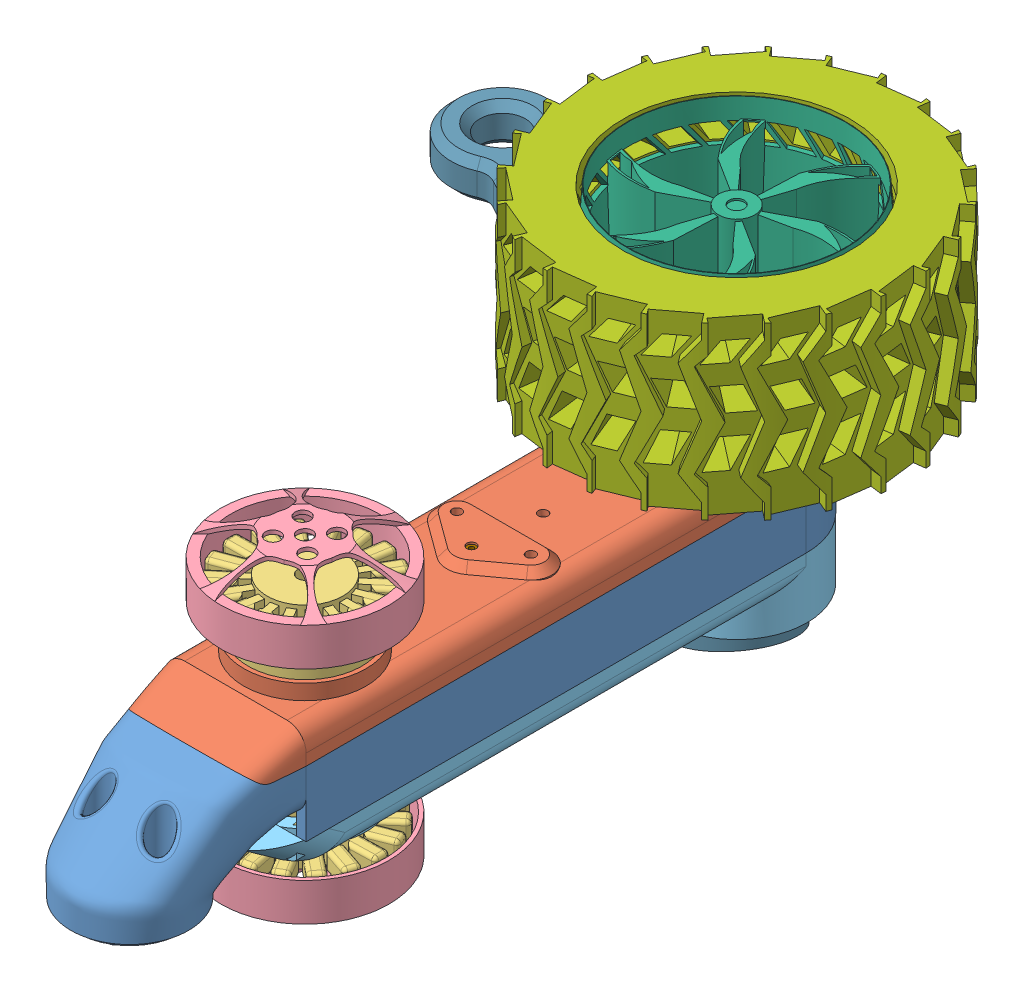
SolidWorks assembly actuator core v2, configuration Default. Lengths in mm.
Overall size (225.57 108.76 271.87).
33 component instances, 15 part files, 37 mates.
Components (placement in the parent):
- upper leg module shell base_v2-1: upper leg module shell base_v2 [Default] at (33.8696 112.35 155.1525) x (-1 0 0) z (0 0 -1) size (37.03 37.51 198.25)
- upper leg module cover_v2-1: upper leg module cover_v2 [Default] at (33.8696 118.35 148.7817) x (0 0 1) z (-1 0 0) size (170.23 17.96 37.06)
- T-motor 4004 kv300-1: T-motor 4004 kv300 [Default] at (68.2159 118.2197 199.3062) x (-0.164171 0 0.986432) z (-0.986432 0 -0.164171) size (60.94 23.74 60.94)
  - motor rotor-1: motor rotor [Default] at (14.1676 19.6303 32.4608) size (40 13.5 39.72)
  - motor stator-1: motor stator [Default] at (14.1676 19.6303 32.4608) x (0.854442 0 0.519546) z (0 1 0) size (44.35 44.35 16.24)
- upper leg module cover_v2_2-1: upper leg module cover_v2_2 [Default] at (33.8696 101.1 148.7817) x (0 0 1) z (1 0 0) size (161.8 16.02 37)
- T-motor 4004 kv300-2: T-motor 4004 kv300 [Default] at (10.1319 109.2303 234.2383) x (0.948296 0 0.317387) z (0.317387 0 -0.948296) size (60.94 23.74 60.94)
  - motor rotor-1: motor rotor [Default] at (14.1676 19.6303 32.4608) size (40 13.5 39.72)
  - motor stator-1: motor stator [Default] at (14.1676 19.6303 32.4608) x (0.854442 0 0.519546) z (0 1 0) size (44.35 44.35 16.24)
- Wheel assembly with motor-1: Wheel assembly with motor [Default] at (75.6805 196.4252 90.9747) x (-0.546944 0 0.837169) z (0 -1 0) size (125.19 125.19 45)
  - wheel-1: wheel [Default] at (25.5285 33.2647 43.0752) size (60 60 45) (hidden)
  - tyre-1: tyre [Default] at (25.5285 33.2647 65.5752) x (0 0 -1) z (0.823199 0.567753 0) size (45 90 90) (hidden)
- centre pulley-1: centre pulley [Default] at (48.6362 100.0034 142.2312) x (0.62745 0 0.778657) z (-0.778657 0 0.62745) size (30 19 30)
  - transmission pulley centre-1: transmission pulley centre [Default] at (7.726 11.8465 25.1899) size (30 6.8 30)
  - centre pulley-1: centre pulley [Default] at (7.726 25.3465 25.1899) x (0.694658 0 -0.71934) z (0 -1 0) size (8.98 9.1 19)
- motor assembly-1: motor assembly [Default] at (33.8696 146.45 207.9525) x (0.833002 0 0.55327) z (-0.55327 0 0.833002) size (16.67 11.86 16.67)
  - motor pulley-1: motor pulley [Default] at (0 -20.1 0) x (1 0 0) z (0 -1 0) size (8.98 9.1 6.7)
  - encoder wheel mount-1: encoder wheel mount [Default] at (0 -28.3 0) x (-0.562764 0 0.826618) z (-0.826618 0 -0.562764) size (12 5.96 12)
- bearing 8mm x 3mm x 3mm-1: bearing 8mm x 3mm x 3mm [Default] at (33.8696 107.85 164.0525) x (-0.837169 0 -0.546944) z (0 1 0) size (7.96 7.96 3)
- bearing 8mm x 3mm x 3mm-2: bearing 8mm x 3mm x 3mm [Default] at (33.8696 105.85 164.0525) x (-0.433108 0 -0.901342) z (0 -1 0) size (7.96 7.96 3)
- centre pulley-2: centre pulley [Default] at (26.1436 113.6965 189.2423) x (1 0 0) z (0 0 -1) size (30 19 30)
  - transmission pulley centre-1: transmission pulley centre [Default] at (7.726 11.8465 25.1899) size (30 6.8 30)
  - centre pulley-1: centre pulley [Default] at (7.726 25.3465 25.1899) x (0.694658 0 -0.71934) z (0 -1 0) size (8.98 9.1 19)
- motor assembly-2: motor assembly [Default] at (33.8696 75.45 207.9525) x (-0.884301 0 -0.466918) z (-0.466918 0 0.884301) size (16.67 11.86 16.67)
  - motor pulley-1: motor pulley [Default] at (0 -20.1 0) x (1 0 0) z (0 -1 0) size (8.98 9.1 6.7)
  - encoder wheel mount-1: encoder wheel mount [Default] at (0 -28.3 0) x (-0.562764 0 0.826618) z (-0.826618 0 -0.562764) size (12 5.96 12)
- bearing 32x25x4mm-1: bearing 32x25x4mm [Default] at (33.8696 125.85 94.1525) x (0.997693 0 -0.067886) z (0.067886 0 0.997693) size (32 4 32)
- bearing 32x25x4mm-2: bearing 32x25x4mm [Default] at (33.8696 87.09 94.1525) x (0.713696 0 0.700456) z (-0.700456 0 0.713696) size (32 4 32)
- lower leg-2: lower leg [Default] at (-35.9818 71.09 55.1552) x (-0.873142 0 -0.487466) z (0.487466 0 -0.873142) size (187 20 27)
- Wheel assembly with motor-2: Wheel assembly with motor [Default] at (65.2193 200.4252 121.9993) x (-0.982016 0 0.188797) z (0 -1 0) size (125.19 125.19 45)
  - wheel-1: wheel [Default] at (25.5285 33.2647 43.0752) size (60 60 45) (hidden)
  - tyre-1: tyre [Default] at (25.5285 33.2647 65.5752) x (0 0 -1) z (0.823199 0.567753 0) size (45 90 90) (hidden)
- transmission pulley output-1: transmission pulley output [Default] at (33.8696 99.14 94.1525) x (-0.487466 0 0.873142) z (0.873142 0 0.487466) size (29 16.4 29)
Mates (geometry in assembly coordinates):
- Coincident1: coincident anti-aligned: plane of upper leg module shell base_v2-1 through (15.3696 118.35 115.1525) normal (0 1 0); plane of upper leg module cover_v2-1 through (33.8696 118.35 148.7817) normal (0 -1 0)
- Coincident2: coincident anti-aligned: plane of upper leg module shell base_v2-1 through (52.3737 75.9862 185.6653) normal (0 0.766044 -0.642788); plane of upper leg module cover_v2-1 through (52.4196 75.3282 184.8812) normal (0 -0.766044 0.642788)
- Coincident3: coincident aligned: plane of upper leg module shell base_v2-1 through (52.3696 106.35 115.1525) normal (1 0 0); plane of upper leg module cover_v2-1 through (52.3696 126.35 226.1517) normal (1 0 0)
- Concentric1: concentric aligned: cylinder of upper leg module cover_v2-1 through (33.8696 130.35 207.9525) axis (0 -1 0) radius 16.1235; circle of T-motor 4004 kv300-1/motor rotor-1
- Coincident4: coincident anti-aligned: plane of upper leg module cover_v2-1 through (33.8696 130.35 207.9525) normal (0 1 0); plane of T-motor 4004 kv300-1/motor rotor-1 through (33.8696 130.35 207.9525) normal (0 -1 0)
- Coincident5: coincident anti-aligned: plane of upper leg module shell base_v2-1 through (33.8696 101.1 155.1525) normal (0 -1 0); plane of upper leg module cover_v2_2-1 through (33.8696 101.1 148.7817) normal (0 1 0)
- Coincident6: coincident aligned: plane of upper leg module shell base_v2-1 through (52.3696 106.35 115.1525) normal (1 0 0); plane of upper leg module cover_v2_2-1 through (52.3696 93.1 226.1517) normal (1 0 0)
- Concentric2: concentric aligned: cylinder of upper leg module cover_v2-1 through (33.8696 130.35 207.9525) axis (0 -1 0) radius 16.1235; cylinder of upper leg module cover_v2_2-1 through (33.8696 98.1 207.9525) axis (0 -1 0) radius 12.5
- Concentric5: concentric anti-aligned: cylinder of upper leg module cover_v2_2-1 through (33.8696 97.1 207.9525) axis (0 1 0) radius 16.1235; cylinder of T-motor 4004 kv300-2/motor rotor-1 through (33.8696 94.6 207.9525) axis (0 -1 0) radius 6
- Coincident7: coincident aligned: plane of upper leg module cover_v2_2-1 through (33.8696 97.1 207.9525) normal (0 1 0); plane of T-motor 4004 kv300-2/motor rotor-1 through (33.8696 97.1 207.9525) normal (0 1 0)
- Coincident9: coincident anti-aligned: plane of upper leg module cover_v2-1 through (33.8696 132.35 94.1525) normal (0 1 0); plane of Wheel assembly with motor-1/wheel-1 through (33.8696 132.35 94.1525) normal (0 -1 0)
- Concentric7: concentric anti-aligned: cylinder of upper leg module cover_v2-1 through (33.8696 120.35 94.1525) axis (0 1 0) radius 16.4954; cylinder of Wheel assembly with motor-1/wheel-1 through (33.8696 156.35 94.1525) axis (0 -1 0) radius 9.4958
- Concentric8: concentric aligned: cylinder of upper leg module cover_v2_2-1 through (33.8696 101.1005 94.1525) axis (0 -1 0) radius 14.25; cylinder of lower leg-1 through (33.8696 81.09 94.1525) axis (0 -1 0) radius 13.5
- Coincident10: coincident anti-aligned: plane of upper leg module cover_v2_2-1 through (33.8696 85.09 94.1525) normal (0 -1 0); plane of lower leg-1 through (33.8696 85.09 94.1525) normal (0 1 0)
- Concentric9: concentric anti-aligned: circle of T-motor 4004 kv300-1/motor rotor-1; cylinder of motor assembly-1/motor shaft-1 through (33.8696 113.05 207.9525) axis (0 1 0) radius 1.995
- Distance1: distance = 4 mm anti-aligned: plane of T-motor 4004 kv300-1/motor rotor-1 through (33.8696 130.35 207.9525) normal (0 -1 0); plane of motor assembly-1/motor pulley-1 through (33.8696 126.35 207.9525) normal (0 1 0)
- Concentric10: concentric aligned: cylinder of bearing 8mm x 3mm x 3mm-1 through (33.8696 110.85 164.0525) axis (0 -1 0) radius 3.98; cylinder of upper leg module shell base_v2-1 through (33.8696 109.85 164.0525) axis (0 -1 0) radius 3.98
- Coincident12: coincident anti-aligned: plane of upper leg module shell base_v2-1 through (20.3696 107.85 115.1525) normal (0 1 0); plane of bearing 8mm x 3mm x 3mm-1 through (33.8696 107.85 164.0525) normal (0 -1 0)
- Concentric11: concentric anti-aligned: line of centre pulley-1/centre pulley-1 through (33.8696 109.05 164.0525) axis (0 1 0); cylinder of bearing 8mm x 3mm x 3mm-1 through (33.8696 110.85 164.0525) axis (0 -1 0) radius 2
- Coincident13: coincident anti-aligned: plane of centre pulley-1/centre pulley-1 through (33.8696 110.85 164.0525) normal (0 -1 0); circle of bearing 8mm x 3mm x 3mm-1
- Concentric12: concentric aligned: cylinder of upper leg module shell base_v2-1 through (33.8696 104.85 164.0525) axis (0 1 0) radius 3.98; cylinder of bearing 8mm x 3mm x 3mm-2 through (33.8696 102.85 164.0525) axis (0 1 0) radius 2
- Coincident14: coincident anti-aligned: plane of upper leg module shell base_v2-1 through (33.8696 105.85 164.0525) normal (0 -1 0); plane of bearing 8mm x 3mm x 3mm-2 through (33.8696 105.85 164.0525) normal (0 1 0)
- Coincident15: coincident anti-aligned: plane of bearing 8mm x 3mm x 3mm-2 through (33.8696 102.85 164.0525) normal (0 -1 0); plane of centre pulley-2/centre pulley-1 through (33.8696 102.85 164.0525) normal (0 1 0)
- Concentric13: concentric anti-aligned: cylinder of bearing 8mm x 3mm x 3mm-2 through (33.8696 102.85 164.0525) axis (0 1 0) radius 3.98; cylinder of centre pulley-2/transmission pulley centre-1 through (33.8696 102.35 164.0525) axis (0 -1 0) radius 15
- Concentric14: concentric anti-aligned: circle of T-motor 4004 kv300-2/motor rotor-1; cylinder of motor assembly-2/motor shaft-1 through (33.8696 108.85 207.9525) axis (0 -1 0) radius 1.995
- Concentric15: concentric anti-aligned: cylinder of upper leg module cover_v2-1 through (33.8696 120.35 94.1525) axis (0 1 0) radius 16.4954; cylinder of bearing 32x25x4mm-1 through (33.8696 129.85 94.1525) axis (0 -1 0) radius 12.5
- Distance3: distance = 2.5 mm aligned: plane of bearing 32x25x4mm-1 through (33.8696 129.85 94.1525) normal (0 1 0); plane of upper leg module cover_v2-1 through (33.8696 132.35 94.1525) normal (0 1 0)
- Coincident19: coincident aligned: plane of centre pulley-2/transmission pulley centre-1 through (33.8696 95.55 164.0525) normal (0 -1 0); plane of motor assembly-2/motor pulley-1 through (33.8696 95.55 207.9525) normal (0 -1 0)
- Concentric16: concentric anti-aligned: cylinder of upper leg module cover_v2_2-1 through (33.8696 87.09 94.1525) axis (0 1 0) radius 16.5; cylinder of bearing 32x25x4mm-2 through (33.8696 91.09 94.1525) axis (0 -1 0) radius 12.5
- Coincident23: coincident anti-aligned: plane of upper leg module cover_v2_2-1 through (33.8696 87.09 94.1525) normal (0 1 0); plane of bearing 32x25x4mm-2 through (33.8696 87.09 94.1525) normal (0 -1 0)
- Concentric17: concentric anti-aligned: cylinder of bearing 32x25x4mm-1 through (33.8696 129.85 94.1525) axis (0 -1 0) radius 12.5; cone of Wheel assembly with motor-2/wheel-1 through (33.8696 140.35 94.1525) axis (0 1 0)
- Distance4: distance = 2.5 mm anti-aligned: plane of Wheel assembly with motor-2/tyre-1 through (33.8696 134.85 94.1525) normal (0 -1 0); plane of upper leg module cover_v2-1 through (33.8696 132.35 94.1525) normal (0 1 0)
- Concentric18: concentric anti-aligned: cylinder of bearing 32x25x4mm-2 through (33.8696 91.09 94.1525) axis (0 -1 0) radius 12.5; cylinder of transmission pulley output-1 through (33.8696 87.09 94.1525) axis (0 1 0) radius 12.575
- Coincident25: coincident aligned: plane of bearing 32x25x4mm-2 through (33.8696 87.09 94.1525) normal (0 -1 0); plane of transmission pulley output-1 through (33.8696 87.09 94.1525) normal (0 -1 0)
- Coincident26: coincident anti-aligned: plane of lower leg-2 through (43.434 91.09 95.4837) normal (0.873142 0 0.487466); plane of transmission pulley output-1 through (39.2906 103.49 102.9054) normal (-0.873142 0 -0.487466)
- Coincident27: coincident anti-aligned: plane of lower leg-2 through (42.8555 91.09 93.4428) normal (0.487466 0 -0.873142); plane of transmission pulley output-1 through (44.1652 103.49 94.174) normal (-0.487466 0 0.873142)
- Coincident28: coincident anti-aligned: plane of upper leg module cover_v2_2-1 through (33.8696 85.09 94.1525) normal (0 -1 0); plane of lower leg-2 through (33.8696 85.09 94.1525) normal (0 1 0)
